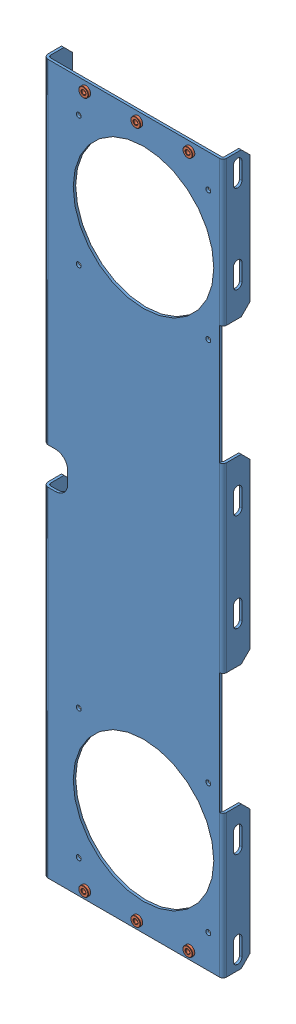
SolidWorks assembly SideChannelLeft, configuration Default. Lengths in mm.
Overall size (150 580 24).
7 component instances, 2 part files, 11 mates.
Components (placement in the parent):
- Part1_F-1: Part1_F [Default] at origin size (150 580 22)
- CLS-M4-0-PennEngineering-01-13-2017_F-1: CLS-M4-0-PennEngineering-01-13-2017_F [Default] at (-115.2 -4 1.23) x (0 0 1) z (-1 0 0) size (2.77 7.87 7.87)
- CLS-M4-0-PennEngineering-01-13-2017_F-2: CLS-M4-0-PennEngineering-01-13-2017_F [Default] at (-72.6 -4 1.23) x (0 0 1) z (-1 0 0) size (2.77 7.87 7.87)
- CLS-M4-0-PennEngineering-01-13-2017_F-3: CLS-M4-0-PennEngineering-01-13-2017_F [Default] at (-30 -4 1.23) x (0 0 1) z (-1 0 0) size (2.77 7.87 7.87)
- CLS-M4-0-PennEngineering-01-13-2017_F-5: CLS-M4-0-PennEngineering-01-13-2017_F [Default] at (-30 -570 1.23) x (0 0 1) z (-1 0 0) size (2.77 7.87 7.87)
- CLS-M4-0-PennEngineering-01-13-2017_F-7: CLS-M4-0-PennEngineering-01-13-2017_F [Default] at (-115.2 -570 1.23) x (0 0 1) z (-1 0 0) size (2.77 7.87 7.87)
- CLS-M4-0-PennEngineering-01-13-2017_F-9: CLS-M4-0-PennEngineering-01-13-2017_F [Default] at (-72.6 -570 1.23) x (0 0 1) z (-1 0 0) size (2.77 7.87 7.87)
Mates (geometry in assembly coordinates):
- Coincident166: coincident: plane of CLS-M4-0-PennEngineering-01-13-2017_F-1 through (-117.0495 -4 4) normal (0 0 1); plane of CLS-M4-0-PennEngineering-01-13-2017_F-2 through (-74.4495 -4 4) normal (0 0 1)
- Coincident165: coincident: plane of CLS-M4-0-PennEngineering-01-13-2017_F-2 through (-74.4495 -4 4) normal (0 0 1); plane of CLS-M4-0-PennEngineering-01-13-2017_F-3 through (-31.8495 -4 4) normal (0 0 1)
- Concentric137: concentric: cylinder of Part1_F-1 through (-115.2 -4 2) axis (0 0 -1) radius 2.5; cylinder of CLS-M4-0-PennEngineering-01-13-2017_F-1 through (-115.2 -4 2.8819) axis (0 0 1) radius 3.935
- Coincident167: coincident: plane of Part1_F-1 through (12 -355 2) normal (0 0 1); plane of CLS-M4-0-PennEngineering-01-13-2017_F-1 through (-117.1675 -4 2) normal (0 0 -1)
- Concentric138: concentric: cylinder of Part1_F-1 through (-30 -4 2) axis (0 0 -1) radius 2.5; cylinder of CLS-M4-0-PennEngineering-01-13-2017_F-3 through (-30 -4 2.8819) axis (0 0 1) radius 3.935
- Concentric139: concentric anti-aligned: cylinder of Part1_F-1 through (-115.2 -570 2) axis (0 0 -1) radius 2.5; cylinder of CLS-M4-0-PennEngineering-01-13-2017_F-7 through (-115.2 -570 2.8819) axis (0 0 1) radius 3.935
- Concentric140: concentric anti-aligned: cylinder of Part1_F-1 through (-72.6 -570 2) axis (0 0 -1) radius 2.5; cylinder of CLS-M4-0-PennEngineering-01-13-2017_F-9 through (-72.6 -570 2.8819) axis (0 0 1) radius 3.935
- Concentric141: concentric anti-aligned: cylinder of Part1_F-1 through (-30 -570 2) axis (0 0 -1) radius 2.5; cylinder of CLS-M4-0-PennEngineering-01-13-2017_F-5 through (-30 -570 2.8819) axis (0 0 1) radius 3.935
- Coincident168: coincident aligned: plane of CLS-M4-0-PennEngineering-01-13-2017_F-7 through (-117.1675 -570 2) normal (0 0 -1); plane of CLS-M4-0-PennEngineering-01-13-2017_F-9 through (-74.5675 -570 2) normal (0 0 -1)
- Coincident169: coincident aligned: plane of CLS-M4-0-PennEngineering-01-13-2017_F-5 through (-31.9675 -570 2) normal (0 0 -1); plane of CLS-M4-0-PennEngineering-01-13-2017_F-9 through (-74.5675 -570 2) normal (0 0 -1)
- Coincident170: coincident anti-aligned: plane of Part1_F-1 through (12 -355 2) normal (0 0 1); plane of CLS-M4-0-PennEngineering-01-13-2017_F-5 through (-31.9675 -570 2) normal (0 0 -1)
